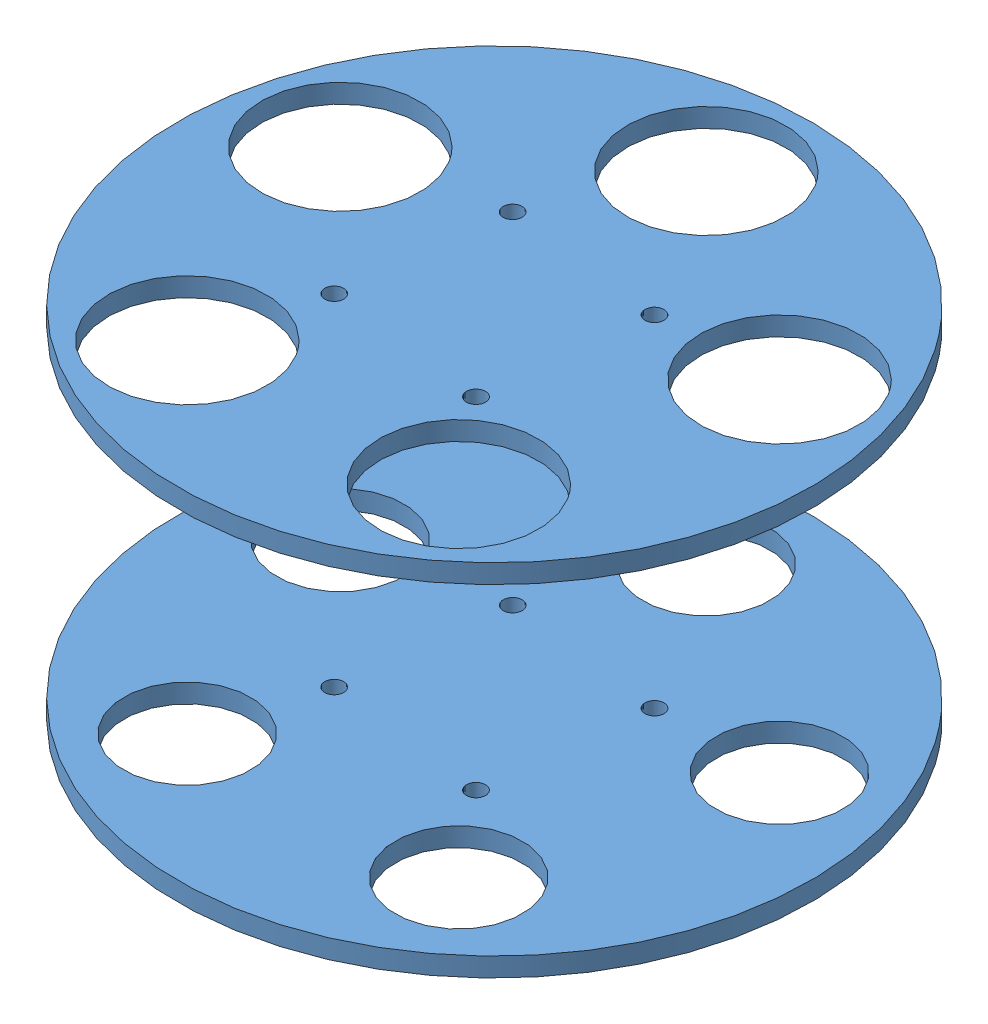
SolidWorks assembly TurntableAssembly, configuration Default. Lengths in mm.
Overall size (140.5 56.8 140.5).
6 component instances, 3 part files, 6 mates.
Components (placement in the parent):
- Holder-2: Holder [Default] at origin (suppressed, hidden)
- RackTopBottom - Updated-3: RackTopBottom - Updated [Default] at (0 5 0) x (-0.782964 0 0.622067) z (0 1 0) size (100 100 56.8)
- Poles-1: Poles [Default] at (14.0933 -62 -11.1972) x (0.985835 0 0.167719) z (-0.167719 0 0.985835) (suppressed, hidden)
- Poles-3: Poles [Default] at (-11.1972 -62 -14.0933) (suppressed, hidden)
- Poles-4: Poles [Default] at (-14.0933 -62 11.1972) (suppressed, hidden)
- Poles-5: Poles [Default] at (11.1972 -62 14.0933) (suppressed, hidden)
Mates (geometry in assembly coordinates):
- Coincident7: coincident anti-aligned: plane of Holder-2 through (0 5 0) normal (0 1 0); plane of RackTopBottom - Updated-3 through (0 5 0) normal (0 -1 0)
- Concentric2: concentric aligned: circle of Holder-2; circle of RackTopBottom - Updated-3
- Coincident8: coincident anti-aligned: circle of RackTopBottom - Updated-3; circle of Poles-1
- Coincident9: coincident anti-aligned: circle of RackTopBottom - Updated-3; circle of Poles-3
- Coincident10: coincident anti-aligned: circle of RackTopBottom - Updated-3; circle of Poles-4
- Coincident11: coincident anti-aligned: circle of RackTopBottom - Updated-3; circle of Poles-5
